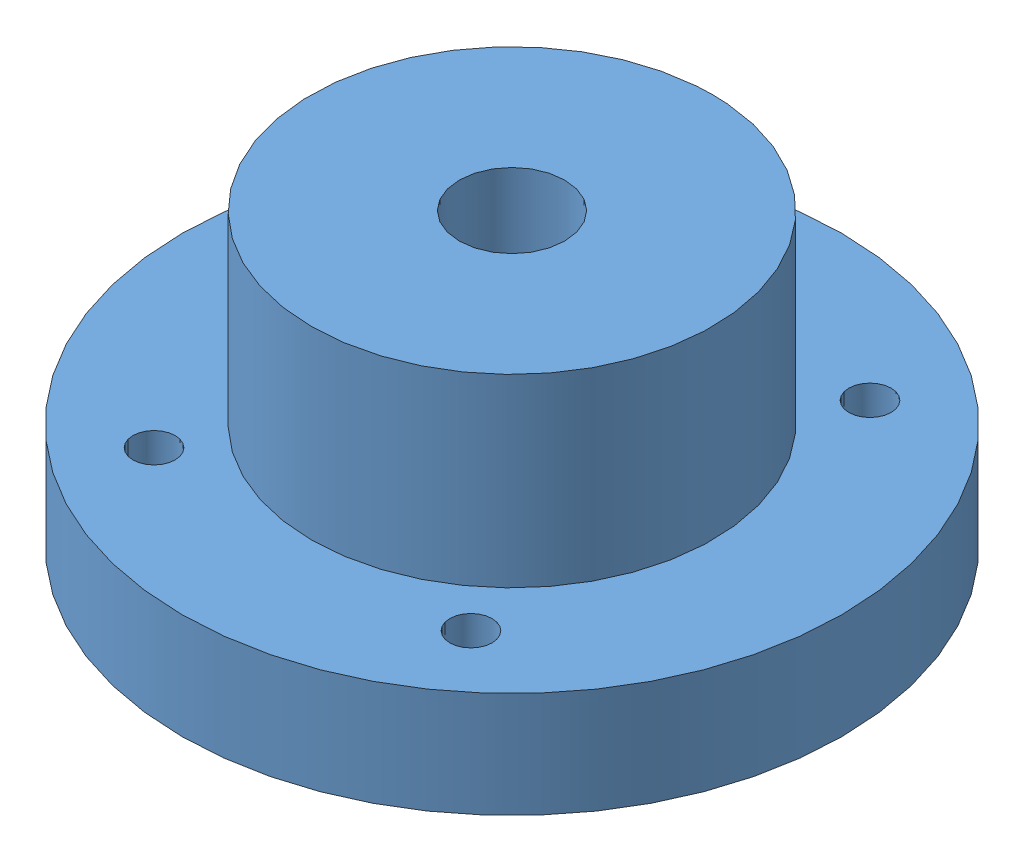
SolidWorks assembly Montagem_carga, configuration Valor predeterminado. Lengths in mm.
Overall size (125 55 125).
32 component instances, 8 part files, 20 mates.
Components (placement in the parent):
- Montagem_plataforma_patins-1: Montagem_plataforma_patins [Valor predeterminado] at (25.6393 2.9651 165.4695) size (315 49.52 108.05) (hidden)
  - Plataforma-1: Plataforma [Valor predeterminado] at (-35.8421 -14.4528 149.5555) size (315 19.02 100)
  - KRH25-FL-N-Z0-1: KRH25-FL-N-Z0 [Valor predeterminado] at (79.1579 -44.9528 191.5555) x (0 0 -1) z (0 1 0) size (96 70 30.5)
  - KRH25-FL-N-Z0-2: KRH25-FL-N-Z0 [Valor predeterminado] at (-150.8421 -44.9528 107.5055) x (0 0 1) z (0 1 0) size (96 70 30.5)
  - Allen_M6x30-1: Allen_M6x30 [Valor predeterminado] at (107.6579 -33.4328 127.0555) x (1 0 0) z (0 1 0) size (10 10 38)
  - Allen_M6x30-2: Allen_M6x30 [Valor predeterminado] at (107.6579 -33.4328 172.0555) x (1 0 0) z (0 1 0) size (10 10 38)
  - Allen_M6x30-3: Allen_M6x30 [Valor predeterminado] at (-179.3421 -33.4328 172.0055) x (1 0 0) z (0 1 0) size (10 10 38)
  - Allen_M6x30-4: Allen_M6x30 [Valor predeterminado] at (-122.3421 -33.4328 172.0055) x (1 0 0) z (0 1 0) size (10 10 38)
  - Allen_M6x30-5: Allen_M6x30 [Valor predeterminado] at (-179.3421 -33.4328 127.0055) x (1 0 0) z (0 1 0) size (10 10 38)
  - Allen_M6x30-6: Allen_M6x30 [Valor predeterminado] at (-122.3421 -33.4328 127.0055) x (1 0 0) z (0 1 0) size (10 10 38)
  - Allen_M6x30-7: Allen_M6x30 [Valor predeterminado] at (50.6579 -33.4328 127.0555) x (1 0 0) z (0 1 0) size (10 10 38)
  - Allen_M6x30-8: Allen_M6x30 [Valor predeterminado] at (50.6579 -33.4328 172.0555) x (1 0 0) z (0 1 0) size (10 10 38)
- Montagem_plataforma_patins-2: Montagem_plataforma_patins [Valor predeterminado] at (25.6393 2.9651 265.4695) size (315 49.52 108.05) (hidden)
  - Plataforma-1: Plataforma [Valor predeterminado] at (-35.8421 -14.4528 149.5555) size (315 19.02 100)
  - KRH25-FL-N-Z0-1: KRH25-FL-N-Z0 [Valor predeterminado] at (79.1579 -44.9528 191.5555) x (0 0 -1) z (0 1 0) size (96 70 30.5)
  - KRH25-FL-N-Z0-2: KRH25-FL-N-Z0 [Valor predeterminado] at (-150.8421 -44.9528 107.5055) x (0 0 1) z (0 1 0) size (96 70 30.5)
  - Allen_M6x30-1: Allen_M6x30 [Valor predeterminado] at (107.6579 -33.4328 127.0555) x (1 0 0) z (0 1 0) size (10 10 38)
  - Allen_M6x30-2: Allen_M6x30 [Valor predeterminado] at (107.6579 -33.4328 172.0555) x (1 0 0) z (0 1 0) size (10 10 38)
  - Allen_M6x30-3: Allen_M6x30 [Valor predeterminado] at (-179.3421 -33.4328 172.0055) x (1 0 0) z (0 1 0) size (10 10 38)
  - Allen_M6x30-4: Allen_M6x30 [Valor predeterminado] at (-122.3421 -33.4328 172.0055) x (1 0 0) z (0 1 0) size (10 10 38)
  - Allen_M6x30-5: Allen_M6x30 [Valor predeterminado] at (-179.3421 -33.4328 127.0055) x (1 0 0) z (0 1 0) size (10 10 38)
  - Allen_M6x30-6: Allen_M6x30 [Valor predeterminado] at (-122.3421 -33.4328 127.0055) x (1 0 0) z (0 1 0) size (10 10 38)
  - Allen_M6x30-7: Allen_M6x30 [Valor predeterminado] at (50.6579 -33.4328 127.0555) x (1 0 0) z (0 1 0) size (10 10 38)
  - Allen_M6x30-8: Allen_M6x30 [Valor predeterminado] at (50.6579 -33.4328 172.0555) x (1 0 0) z (0 1 0) size (10 10 38)
- Junção carrinhos-1: Junção carrinhos [Valor predeterminado] at (-10.2028 7.5324 365.025) x (0 1 0) z (0 0 1) size (55 125 125)
- Torre_central-1: Torre_central [Valor predeterminado] at (-10.2028 37.5324 365.025) size (20 80 20) (hidden)
- Peso 5kg-1: Peso 5kg [Valor predeterminado] at (-10.2028 62.5324 365.025) x (0.999979 0 0.006537) z (-0.006537 0 0.999979) size (200 20 200) (hidden)
- Peso 2kg-1: Peso 2kg [Valor predeterminado] at (-10.2028 102.5324 365.025) x (-0.320752 0 0.947163) z (0.947163 0 0.320752) size (150 20 150) (hidden)
- DIN912_ISO 4762 - B-1: DIN912_ISO 4762 - B [ISO 4762 M8 x 50] at (-40.2028 35.5324 327.25) x (0 -1 0) z (0 0 1) size (58 13 13) (hidden)
- DIN912_ISO 4762 - B-2: DIN912_ISO 4762 - B [ISO 4762 M8 x 50] at (19.7972 35.5324 327.25) x (0 -1 0) z (0 0 1) size (58 13 13) (hidden)
- DIN912_ISO 4762 - B-3: DIN912_ISO 4762 - B [ISO 4762 M8 x 50] at (-40.2028 35.5324 402.8) x (0 -1 0) z (-0.298856 0 0.954298) size (58 13 13) (hidden)
- DIN912_ISO 4762 - B-4: DIN912_ISO 4762 - B [ISO 4762 M8 x 50] at (19.7972 35.5324 402.8) x (0 -1 0) z (0 0 1) size (58 13 13) (hidden)
Mates (geometry in assembly coordinates):
- Concêntrico1: concentric: cylinder of Montagem_plataforma_patins-1/Plataforma-1 through (-40.2028 7.5324 327.25) axis (0 1 0) radius 7.5; cylinder of Junção carrinhos-1 through (-40.2028 27.5324 327.25) axis (0 -1 0) radius 4
- Coincidente1: coincident anti-aligned: plane of Montagem_plataforma_patins-1/Plataforma-1 through (-10.2028 7.5324 315.025) normal (0 1 0); plane of Junção carrinhos-1 through (-10.2028 7.5324 365.025) normal (0 -1 0)
- Concêntrico2: concentric aligned: circle of Montagem_plataforma_patins-1/Plataforma-1; circle of Junção carrinhos-1
- Concêntrico3: concentric aligned: circle of Montagem_plataforma_patins-2/Plataforma-1; circle of Junção carrinhos-1
- Coincidente2: coincident anti-aligned: plane of Montagem_plataforma_patins-2/Plataforma-1 through (-10.2028 7.5324 415.025) normal (0 1 0); plane of Junção carrinhos-1 through (-10.2028 7.5324 365.025) normal (0 -1 0)
- Concêntrico4: concentric anti-aligned: cylinder of Junção carrinhos-1 through (-10.2028 37.5324 365.025) axis (0 1 0) radius 10; cylinder of Torre_central-1 through (-10.2028 117.5324 365.025) axis (0 -1 0) radius 10
- Coincidente3: coincident aligned: plane of Junção carrinhos-1 through (-10.2028 37.5324 365.025) normal (0 1 0); circle of Torre_central-1
- Concêntrico5: concentric anti-aligned: circle of Junção carrinhos-1; cylinder of Peso 5kg-1 through (-10.2028 82.5324 365.025) axis (0 -1 0) radius 16.5
- Coincidente5: coincident aligned: plane of Junção carrinhos-1 through (-10.2028 62.5324 365.025) normal (0 1 0); circle of Peso 5kg-1
- Coincidente6: coincident anti-aligned: plane of Peso 5kg-1 through (-10.2028 82.5324 365.025) normal (0 1 0); plane of Peso 2kg-1 through (-10.2028 82.5324 365.025) normal (0 -1 0)
- Concêntrico6: concentric anti-aligned: cylinder of Peso 5kg-1 through (-10.2028 82.5324 365.025) axis (0 -1 0) radius 100; cylinder of Peso 2kg-1 through (-10.2028 82.5324 365.025) axis (0 1 0) radius 75
- Coincidente10: coincident anti-aligned: plane of Montagem_plataforma_patins-1/Plataforma-1 through (-167.7028 7.5324 365.025) normal (0 0 1); plane of Montagem_plataforma_patins-2/Plataforma-1 through (-167.7028 7.5324 365.025) normal (0 0 -1)
- Concêntrico81: concentric anti-aligned: cylinder of Junção carrinhos-1 through (-40.2028 27.5324 327.25) axis (0 -1 0) radius 4; cylinder of DIN912_ISO 4762 - B-1 through (-40.2028 67.2824 327.25) axis (0 1 0) radius 6.5
- Coincidente111: coincident anti-aligned: plane of Junção carrinhos-1 through (-10.2028 27.5324 365.025) normal (0 1 0); plane of DIN912_ISO 4762 - B-1 through (-33.7028 27.5324 327.25) normal (0 -1 0)
- Concêntrico91: concentric anti-aligned: cylinder of Junção carrinhos-1 through (19.7972 27.5324 327.25) axis (0 -1 0) radius 4; cylinder of DIN912_ISO 4762 - B-2 through (19.7972 67.2824 327.25) axis (0 1 0) radius 6.5
- Coincidente121: coincident anti-aligned: plane of Junção carrinhos-1 through (-10.2028 27.5324 365.025) normal (0 1 0); plane of DIN912_ISO 4762 - B-2 through (26.2972 27.5324 327.25) normal (0 -1 0)
- Concêntrico101: concentric anti-aligned: cylinder of Junção carrinhos-1 through (-40.2028 27.5324 402.8) axis (0 -1 0) radius 4; cylinder of DIN912_ISO 4762 - B-3 through (-40.2028 67.2824 402.8) axis (0 1 0) radius 6.5
- Coincidente131: coincident anti-aligned: plane of Junção carrinhos-1 through (-10.2028 27.5324 365.025) normal (0 1 0); plane of DIN912_ISO 4762 - B-3 through (-33.9998 27.5324 404.7426) normal (0 -1 0)
- Concêntrico111: concentric anti-aligned: cylinder of Junção carrinhos-1 through (19.7972 27.5324 402.8) axis (0 -1 0) radius 4; cylinder of DIN912_ISO 4762 - B-4 through (19.7972 67.2824 402.8) axis (0 1 0) radius 6.5
- Coincidente141: coincident anti-aligned: plane of Junção carrinhos-1 through (-10.2028 27.5324 365.025) normal (0 1 0); plane of DIN912_ISO 4762 - B-4 through (26.2972 27.5324 402.8) normal (0 -1 0)
